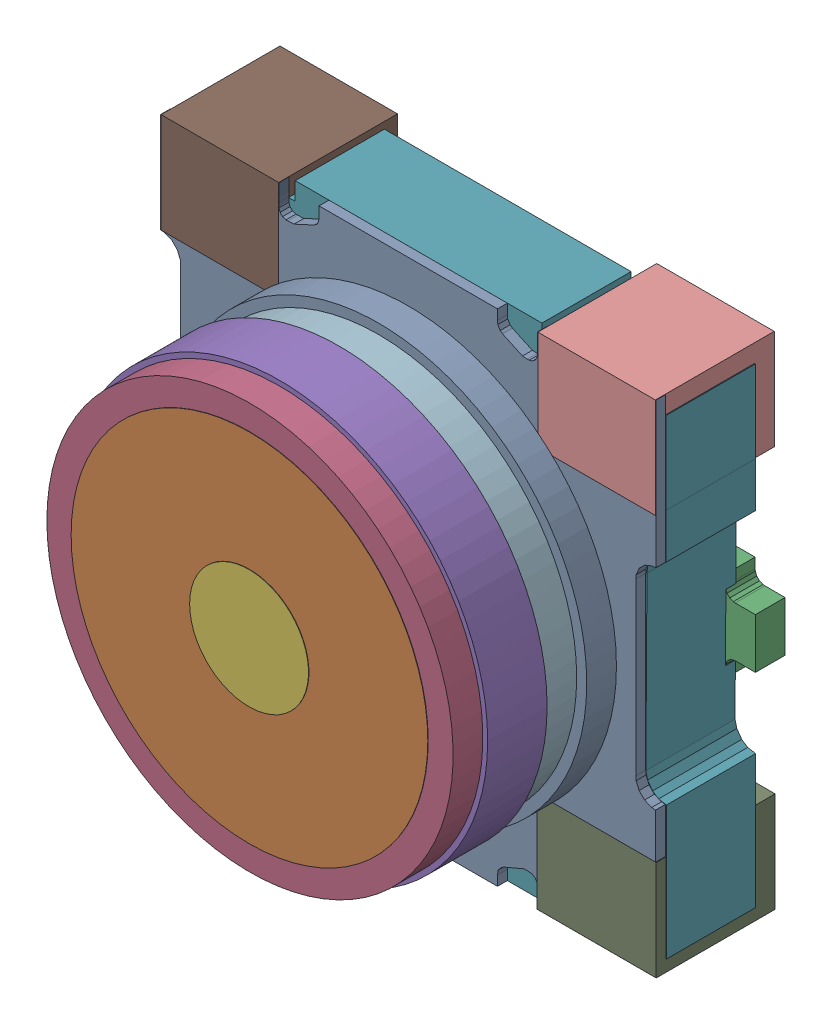
SolidWorks assembly J1.step, configuration Default. Lengths in mm.
Overall size (2.6 2.52 1.4).
28 component instances, 14 part files, 0 mates.
Components (placement in the parent):
- 6401103008.step-1: 6401103008.step [Default] at (127.4221 6.6412 0.55) size (2.5 2.52 0.05)
  - Extruded (1).step-1: Extruded (1).step [Default] at origin size (2.5 2.52 0.05)
- 6401103088.step-1: 6401103088.step [Default] at (126.3242 6.6413 0) size (0.4 0.45 0.15)
  - Extruded (2).step-1: Extruded (2).step [Default] at origin size (0.4 0.45 0.15)
- 6401102928.step-1: 6401102928.step [Default] at (128.4526 6.6413 0) size (0.54 0.45 0.15)
  - Extruded (3).step-1: Extruded (3).step [Default] at origin size (0.54 0.45 0.15)
- 6440846816.step-1: 6440846816.step [Default] at (127.4234 6.6412 1.25) x (1 0 0) z (0 0 1) size (2.05 2.05 0.15)
  - Cylinder.step-1: Cylinder.step [Default] at origin size (2.05 2.05 0.15)
- 6440846496.step-1: 6440846496.step [Default] at (127.4228 6.6412 0.95) x (1 0 0) z (0 0 1) size (2.1 2.1 0.3)
  - Cylinder (1).step-1: Cylinder (1).step [Default] at origin size (2.1 2.1 0.3)
- 6440846176.step-1: 6440846176.step [Default] at (127.4228 6.6412 0.6) x (1 0 0) z (0 0 1) size (0.6 0.6 0.8)
  - Cylinder (2).step-1: Cylinder (2).step [Default] at origin size (0.6 0.6 0.8)
- 6440845936.step-1: 6440845936.step [Default] at (127.4228 6.6413 0.1) size (2.5 2.52 0.45)
  - Extruded (4).step-1: Extruded (4).step [Default] at origin size (2.5 2.52 0.45)
- 6440845696.step-1: 6440845696.step [Default] at (126.4715 5.6317 0) size (0.59 0.5 0.6)
  - Extruded (5).step-1: Extruded (5).step [Default] at origin size (0.59 0.5 0.6)
- 6440845456.step-1: 6440845456.step [Default] at (128.3728 5.6317 0) size (0.6 0.5 0.6)
  - Extruded (6).step-1: Extruded (6).step [Default] at origin size (0.6 0.5 0.6)
- 6440845216.step-1: 6440845216.step [Default] at (128.3727 7.651 0) size (0.59 0.5 0.6)
  - Extruded (7).step-1: Extruded (7).step [Default] at origin size (0.59 0.5 0.6)
- 6440844976.step-1: 6440844976.step [Default] at (126.4714 7.6509 0) size (0.59 0.5 0.6)
  - Extruded (8).step-1: Extruded (8).step [Default] at origin size (0.59 0.5 0.6)
- 6440844656.step-1: 6440844656.step [Default] at (127.4221 6.6413 0.75) x (1 0 0) z (0 0 1) size (2 2 0.2)
  - Cylinder (3).step-1: Cylinder (3).step [Default] at origin size (2 2 0.2)
- 6440844336.step-1: 6440844336.step [Default] at (127.4228 6.6412 0.6) x (1 0 0) z (0 0 1) size (2.1 2.1 0.15)
  - Cylinder (4).step-1: Cylinder (4).step [Default] at origin size (2.1 2.1 0.15)
- 6440844016.step-1: 6440844016.step [Default] at (127.4228 6.6412 0.6) x (1 0 0) z (0 0 1) size (1.8 1.8 0.8)
  - Cylinder (5).step-1: Cylinder (5).step [Default] at origin size (1.8 1.8 0.8)
